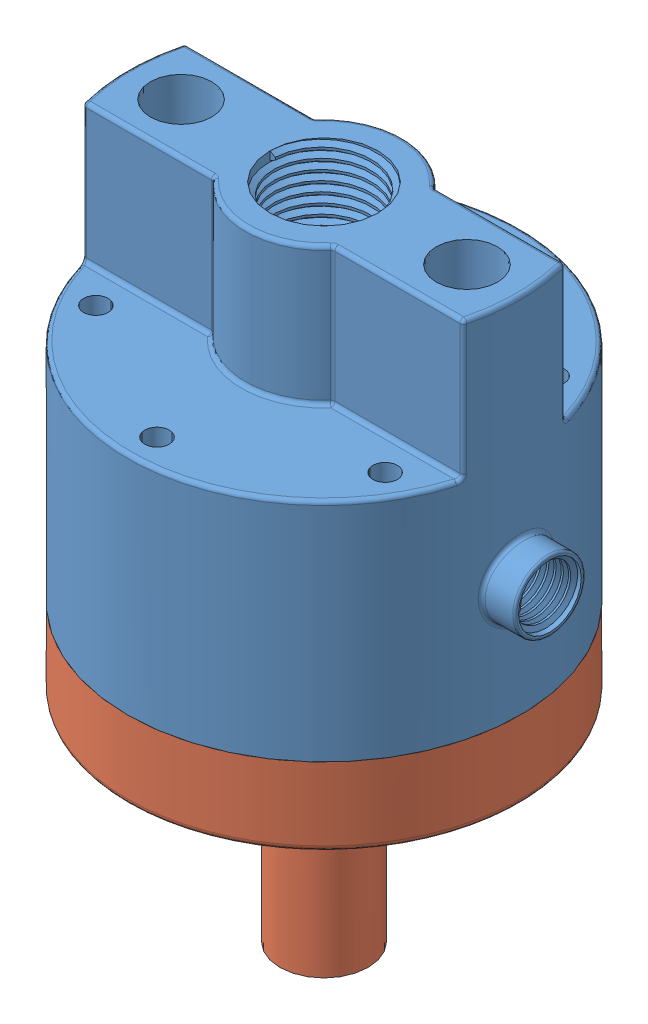
SolidWorks assembly Assem2, configuration Default. Lengths in mm.
Overall size (54.89 85.09 50.8).
2 component instances, 2 part files, 2 mates.
Components (placement in the parent):
- Igniter_Top-1: Igniter_Top [Default] at (75.2297 67.4531 34.9783) x (1 0 0) z (0 1 0) size (54.89 50.8 85.09)
- Ingiter_Tube2-1: Ingiter_Tube2 [Default] at (75.2297 28.0831 34.9783) size (50.8 42.42 50.8)
Mates (geometry in assembly coordinates):
- Concentric3: concentric aligned: cylinder of Igniter_Top-1 through (75.2297 0.1431 34.9783) axis (0 1 0) radius 3.81; cylinder of Ingiter_Tube2-1 through (75.2297 56.4295 34.9783) axis (0 1 0) radius 4.445
- Coincident6: coincident anti-aligned: plane of Igniter_Top-1 through (75.2297 38.2431 9.5783) normal (0 -1 0); plane of Ingiter_Tube2-1 through (66.2127 38.2431 34.9783) normal (0 1 0)
